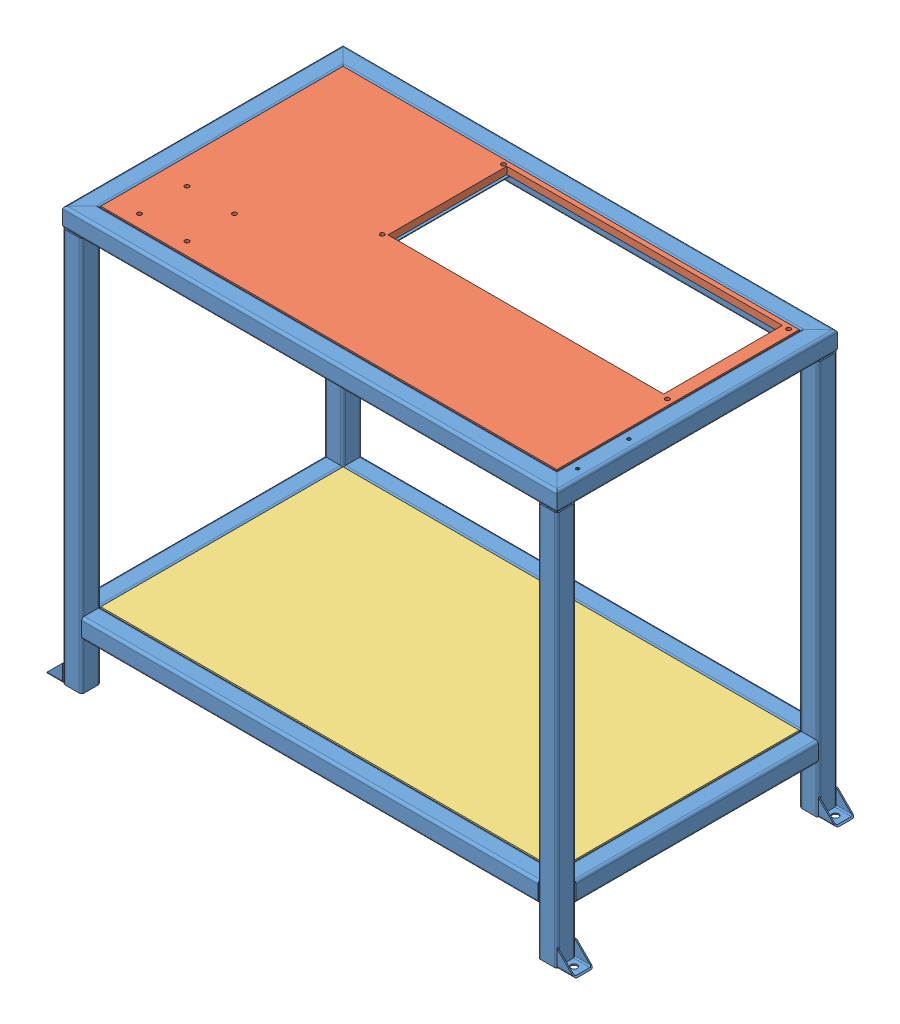
SolidWorks assembly EXTPRO-V1 3000.00-A Frame, configuration Default. Lengths in mm.
Overall size (1200 870 590).
3 component instances, 3 part files, 34 mates.
Components (placement in the parent):
- EXTPRO-V1 3000.01-A Main frame-1: EXTPRO-V1 3000.01-A Main frame [Default<As Machined>] at (0 -20 0) size (1200 870 590)
- EXTPRO-V1 3000.02-A Top shelf-2: EXTPRO-V1 3000.02-A Top shelf [Default] at (0 -7.5 0) size (960 15 510)
- EXTPRO-V1 3000.03-A Bottom shelf-1: EXTPRO-V1 3000.03-A Bottom shelf [Default] at (0 -737.5 0) size (960 15 510)
Mates (geometry in assembly coordinates):
- Coincident1: coincident aligned: plane of EXTPRO-V1 3000.01-A Main frame-1 through (-514.8 0 -275) normal (0 1 0)
- Coincident2: coincident aligned: plane of EXTPRO-V1 3000.01-A Main frame-1 through (0 -20 0) normal (0 0 1)
- Coincident3: coincident aligned: plane of EXTPRO-V1 3000.01-A Main frame-1 through (0 -20 0) normal (1 0 0)
- Coincident4: coincident anti-aligned: plane of EXTPRO-V1 3000.01-A Main frame-1 through (-480 -34.8 -275) normal (1 0 0); plane of ? through (-480 -15 -219.6447) normal (-1 0 0)
- Distance1: distance = 15 mm aligned: plane of EXTPRO-V1 3000.01-A Main frame-1 through (-514.8 0 -275) normal (0 1 0); plane of ? through (-462.3223 -15 -237.3223) normal (0 1 0)
- Coincident6: coincident anti-aligned: plane of EXTPRO-V1 3000.01-A Main frame-1 through (500 -34.8 -255) normal (0 0 1); plane of ? through (444.6447 -15 -255) normal (0 0 -1)
- Coincident7: coincident: plane of ? through (462.3223 -15 -237.3223) normal (0 1 0); plane of ? through (-462.3223 -15 -237.3223) normal (0 1 0)
- Coincident8: coincident anti-aligned: plane of EXTPRO-V1 3000.01-A Main frame-1 through (480 -34.8 275) normal (-1 0 0); plane of ? through (480 -15 -184.2893) normal (1 0 0)
- Coincident9: coincident anti-aligned: plane of EXTPRO-V1 3000.01-A Main frame-1 through (500 -34.8 -255) normal (0 0 1); plane of ? through (-409.2893 -15 -255) normal (0 0 -1)
- Coincident10: coincident anti-aligned: plane of EXTPRO-V1 3000.01-A Main frame-1 through (-480 -34.8 -275) normal (1 0 0); plane of ? through (-480 -15 184.2893) normal (-1 0 0)
- Coincident11: coincident: plane of ? through (-462.3223 -15 -237.3223) normal (0 1 0); plane of ? through (-462.3223 -15 237.3223) normal (0 1 0)
- Coincident12: coincident anti-aligned: plane of EXTPRO-V1 3000.01-A Main frame-1 through (-500 -34.8 255) normal (0 0 -1); plane of ? through (-444.6447 -15 255) normal (0 0 1)
- Coincident13: coincident anti-aligned: plane of EXTPRO-V1 3000.01-A Main frame-1 through (480 -34.8 275) normal (-1 0 0); plane of ? through (480 -15 219.6447) normal (1 0 0)
- Coincident14: coincident: plane of ? through (462.3223 -15 -237.3223) normal (0 1 0); plane of ? through (462.3223 -15 237.3223) normal (0 1 0)
- Coincident15: coincident anti-aligned: plane of EXTPRO-V1 3000.01-A Main frame-1 through (-500 -34.8 255) normal (0 0 -1); plane of ? through (409.2893 -15 255) normal (0 0 1)
- Coincident29: coincident anti-aligned: plane of EXTPRO-V1 3000.01-A Main frame-1 through (480 -764.8 275) normal (-1 0 0); plane of EXTPRO-V1 3000.03-A Bottom shelf-1 through (480 -730 255) normal (1 0 0)
- Coincident30: coincident anti-aligned: plane of EXTPRO-V1 3000.01-A Main frame-1 through (-500 -764.8 255) normal (0 0 -1); plane of EXTPRO-V1 3000.03-A Bottom shelf-1 through (-480 -730 255) normal (0 0 1)
- Coincident43: coincident aligned: plane of EXTPRO-V1 3000.01-A Main frame-1 through (514.8 0 275) normal (0 1 0); plane of EXTPRO-V1 3000.02-A Top shelf-2 through (0 0 0) normal (0 1 0)
- Coincident44: coincident anti-aligned: plane of EXTPRO-V1 3000.01-A Main frame-1 through (-500 -34.8 255) normal (0 0 -1); plane of EXTPRO-V1 3000.02-A Top shelf-2 through (480 0 255) normal (0 0 1)
- Coincident45: coincident anti-aligned: plane of EXTPRO-V1 3000.01-A Main frame-1 through (-480 -34.8 -275) normal (1 0 0); plane of EXTPRO-V1 3000.02-A Top shelf-2 through (-480 0 255) normal (-1 0 0)
- Coincident46: coincident anti-aligned: plane of EXTPRO-V1 3000.01-A Main frame-1 through (-500 -34.8 255) normal (0 0 -1); plane of ? through (-388.25 -15 255) normal (0 0 1)
- Coincident47: coincident: plane of ? through (462.3223 -15 237.3223) normal (0 1 0); plane of ? through (-398.25 -15 0) normal (0 1 0)
- Coincident48: coincident: plane of ? through (-398.25 -15 0) normal (0 1 0); plane of ? through (-227.9875 -15 0) normal (0 1 0)
- Coincident49: coincident anti-aligned: plane of EXTPRO-V1 3000.01-A Main frame-1 through (-500 -34.8 255) normal (0 0 -1); plane of ? through (-217.9875 -15 255) normal (0 0 1)
- Coincident50: coincident: plane of ? through (198.6496 -15 0) normal (0 1 0); plane of ? through (124.1814 -15 0) normal (0 1 0)
- Coincident51: coincident anti-aligned: plane of EXTPRO-V1 3000.01-A Main frame-1 through (-500 -34.8 255) normal (0 0 -1); plane of ? through (134.1814 -15 255) normal (0 0 1)
- Coincident52: coincident: plane of ? through (16.4002 -15 0) normal (0 1 0); plane of ? through (124.1814 -15 0) normal (0 1 0)
- Coincident53: coincident anti-aligned: plane of EXTPRO-V1 3000.01-A Main frame-1 through (-500 -34.8 255) normal (0 0 -1); plane of ? through (26.4002 -15 255) normal (0 0 1)
- Distance3: distance = 75 mm: plane of EXTPRO-V1 3000.01-A Main frame-1 through (-480 -34.8 -275) normal (1 0 0); cylinder of ? through (-398.25 -25 234) axis (0 -1 0) radius 6.75
- Coincident54: coincident anti-aligned: plane of EXTPRO-V1 3000.01-A Main frame-1 through (514.8 0 275) normal (0 1 0); plane of ? through (500 0 177.5) normal (0 -1 0)
- Coincident55: coincident aligned: plane of EXTPRO-V1 3000.01-A Main frame-1 through (520 -5.2 275) normal (1 0 0); plane of ? through (520 0 237.5) normal (1 0 0)
- Concentric1: concentric aligned: cylinder of EXTPRO-V1 3000.01-A Main frame-1 through (500 -49.8995 123.5) axis (0 1 0) radius 3.5; cylinder of ? through (500 6 123.5) axis (0 1 0) radius 3.5
- Coincident56: coincident anti-aligned: plane of EXTPRO-V1 3000.01-A Main frame-1 through (485.2 -40 275) normal (0 -1 0); plane of ? through (500 -40 123.5) normal (0 1 0)
- Coincident57: coincident anti-aligned: plane of EXTPRO-V1 3000.01-A Main frame-1 through (485.2 -40 275) normal (0 -1 0); plane of ? through (500 -40 231.5) normal (0 1 0)
